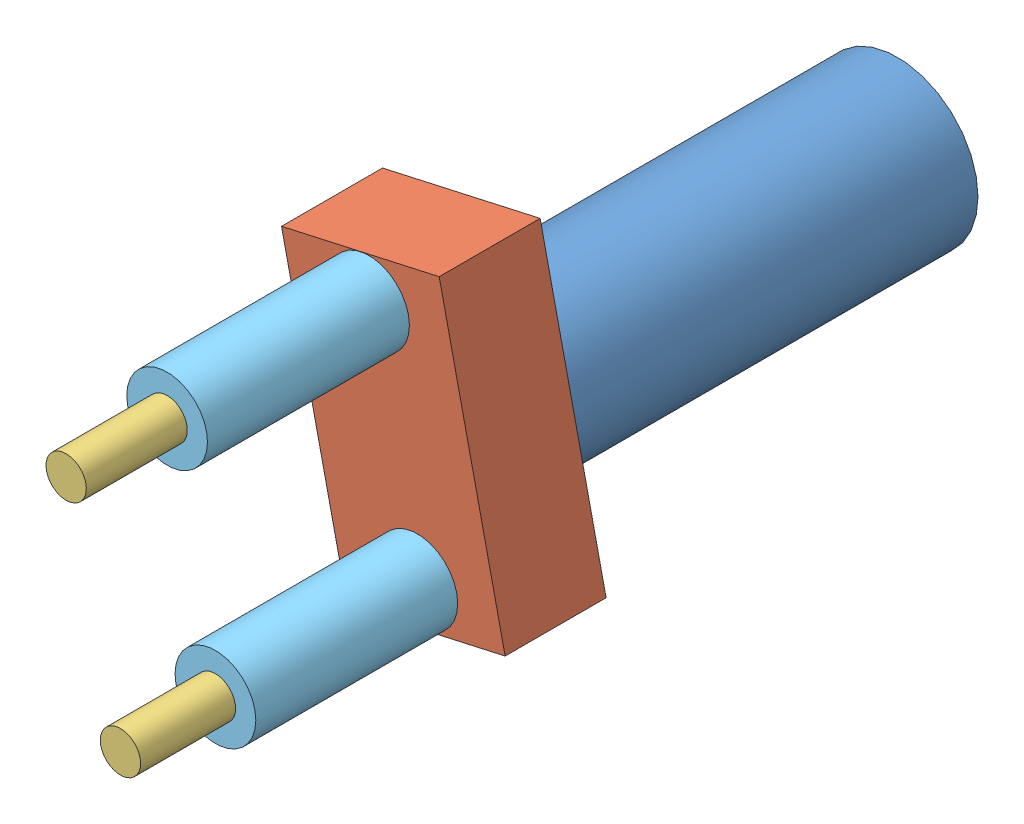
SolidWorks assembly gripper, configuration Default. Lengths in mm.
Overall size (11.08 16.38 39.96).
7 component instances, 5 part files, 7 mates.
Components (placement in the parent):
- grip1-1: grip1 [Default] at origin size (8 8 20)
- grip2-1: grip2 [Default] at (-10.0642 4.2628 19.9555) x (0.217805 -0.975992 0) z (0 0 1) size (15 8 5)
- grip3-1: grip3 [Default] at (-3.3288 -7.5539 34.668) size (2 2 5)
- grip4-1: grip4 [Default] at (-4.8801 -2.0407 0) size (3 3 3)
- grip5-1: grip5 [Default] at (-3.3288 -7.5539 24.9649) size (4 4 10)
- grip3-2: grip3 [Default] at (-5.7247 3.1821 34.9623) x (-0.961993 -0.273073 0) z (0 0 1) size (2 2 5)
- grip5-3: grip5 [Default] at (-5.7247 3.1821 24.9623) size (4 4 10)
Mates (geometry in assembly coordinates):
- Coincident3: coincident anti-aligned: circle of grip1-1; circle of grip4-1
- Concentric2: concentric anti-aligned: circle of grip1-1; circle of grip2-1
- Concentric3: concentric aligned: circle of grip2-1; circle of grip5-1
- Concentric4: concentric aligned: circle of grip3-1; circle of grip5-1
- Concentric6: concentric aligned: circle of grip3-2; circle of grip5-3
- Concentric8: concentric aligned: circle of grip2-1; circle of grip5-3
- Coincident7: coincident anti-aligned: plane of grip3-2 through (-5.7247 3.1821 34.9623) normal (0 0 -1); plane of grip5-3 through (-5.7247 3.1821 34.9623) normal (0 0 1)
